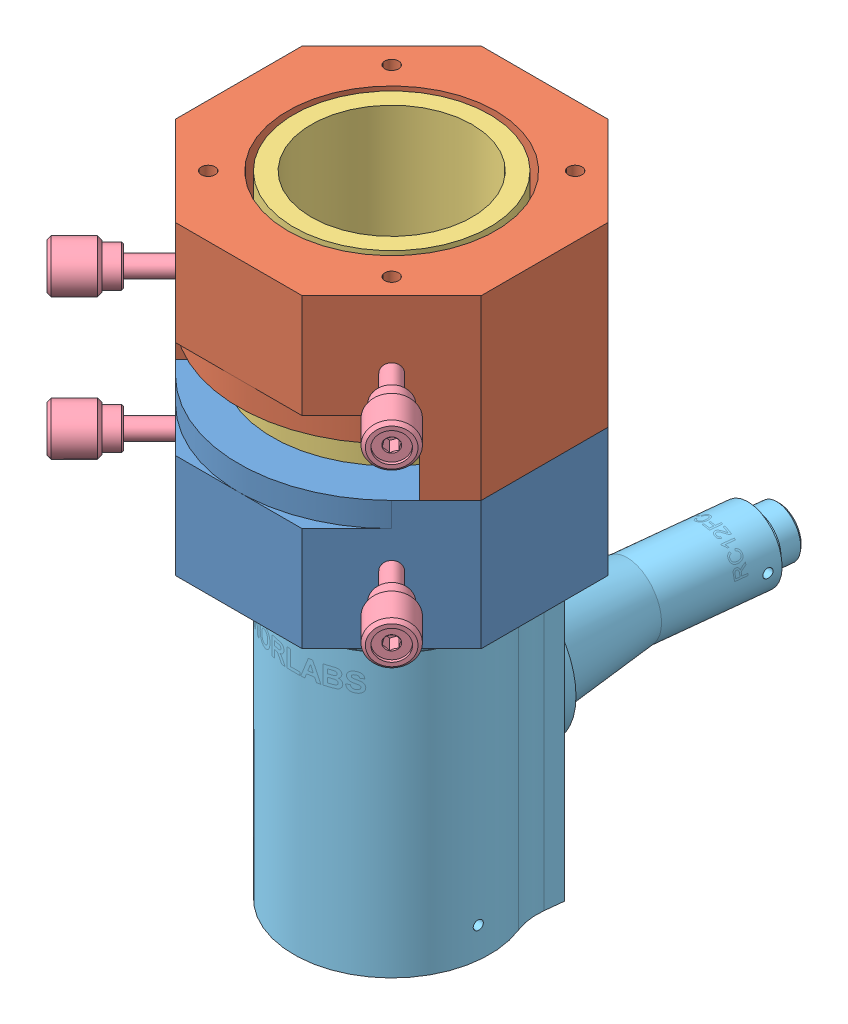
SolidWorks assembly Collimator Allignment Tool, configuration Default. Lengths in mm.
Overall size (62.9 103 91.39).
8 component instances, 5 part files, 15 mates.
Components (placement in the parent):
- CC053-A - Outer Tube Short-1: CC053-A - Outer Tube Short [Default] at (5.4949 13.0758 47.5763) size (50 21 50)
- CC052-A - Outer Tube Long-1: CC052-A - Outer Tube Long [Default] at (5.4949 63.0758 47.5763) x (1 0 0) z (0 0 -1) size (50 29 50)
- CC051-A - Inner Tube-2: CC051-A - Inner Tube [Default] at (5.4949 38.0758 47.5763) x (-0.947211 0 -0.320612) z (0.320612 0 -0.947211) size (39 50 39)
- MAS15-1: MAS15 [Default] at (21.7416 50.6684 64.379) x (-0.146441 -0.97832 0.146441) z (-0.707107 0 -0.707107) size (7.11 7.11 23.88)
- MAS15-2: MAS15 [Default] at (21.7416 22.6684 64.379) x (-0.146441 -0.97832 0.146441) z (-0.707107 0 -0.707107) size (7.11 7.11 23.88)
- MAS15-3: MAS15 [Default] at (-11.8034 50.5446 63.3275) x (-0.558147 0.613957 -0.558147) z (0.707107 0 -0.707107) size (7.11 7.11 23.88)
- MAS15-4: MAS15 [Default] at (-11.8034 27.5446 63.3275) x (-0.558147 0.613957 -0.558147) z (0.707107 0 -0.707107) size (7.11 7.11 23.88)
- RC12FC-P01 - ReflectiveCollimator12mm-1: RC12FC-P01 - ReflectiveCollimator12mm [Default] at (5.4949 -39.9242 47.5763) x (-0.994124 0 -0.10825) z (0 1 0) size (42.2 77.84 57)
Mates (geometry in assembly coordinates):
- Concentric1: concentric: cylinder of CC053-A - Outer Tube Short-1 through (-15.3477 13.0758 56.2096) axis (0 -1 0) radius 1.7; cylinder of CC052-A - Outer Tube Long-1 through (-15.3477 34.0758 56.2096) axis (0 -1 0) radius 1.25
- Concentric2: concentric: cylinder of CC053-A - Outer Tube Short-1 through (26.3374 13.0758 56.2096) axis (0 -1 0) radius 1.7; cylinder of CC052-A - Outer Tube Long-1 through (26.3374 34.0758 56.2096) axis (0 -1 0) radius 1.25
- Coincident5: coincident: plane of CC053-A - Outer Tube Short-1 through (5.4949 34.0758 47.5763) normal (0 1 0); plane of CC052-A - Outer Tube Long-1 through (5.4949 34.0758 47.5763) normal (0 -1 0)
- Concentric4: concentric: cylinder of CC052-A - Outer Tube Long-1 through (5.4949 42.0758 47.5763) axis (0 1 0) radius 17; cylinder of CC051-A - Inner Tube-2 through (5.4949 63.0758 47.5763) axis (0 -1 0) radius 16
- Width5: width: plane of CC052-A - Outer Tube Long-1 through (5.4949 63.0758 47.5763) normal (0 1 0); plane of CC053-A - Outer Tube Short-1 through (5.4949 13.0758 47.5763) normal (0 -1 0); plane of CC051-A - Inner Tube-2 through (5.4949 13.0758 47.5763) normal (0 -1 0); plane of CC051-A - Inner Tube-2 through (5.4949 63.0758 47.5763) normal (0 1 0)
- Concentric6: concentric: cylinder of CC052-A - Outer Tube Long-1 through (23.1725 52.0758 65.254) axis (0.707107 0 0.707107) radius 1.4; cylinder of MAS15-1 through (16.7692 52.0758 58.8506) axis (-0.707107 0 -0.707107) radius 1.5
- Concentric7: concentric: cylinder of CC053-A - Outer Tube Short-1 through (23.1725 24.0758 65.254) axis (0.707107 0 0.707107) radius 1.4; cylinder of MAS15-2 through (16.7692 24.0758 58.8506) axis (-0.707107 0 -0.707107) radius 1.5
- Concentric8: concentric: cylinder of CC052-A - Outer Tube Long-1 through (-12.1828 49.5758 65.254) axis (-0.707107 0 0.707107) radius 1.4; cylinder of MAS15-3 through (-5.7795 49.5758 58.8506) axis (0.707107 0 -0.707107) radius 1.5
- Concentric9: concentric: cylinder of CC053-A - Outer Tube Short-1 through (-12.1828 26.5758 65.254) axis (-0.707107 0 0.707107) radius 1.4; cylinder of MAS15-4 through (-5.7795 26.5758 58.8506) axis (0.707107 0 -0.707107) radius 1.5
- Coincident6: coincident: plane of MAS15-3 through (-19.0992 46.0082 78.657) normal (-0.707107 0 0.707107); plane of MAS15-4 through (-19.0992 23.0082 78.657) normal (-0.707107 0 0.707107)
- Coincident7: coincident: plane of MAS15-1 through (34.1832 57.7607 74.5627) normal (0.707107 0 0.707107); plane of MAS15-2 through (34.1832 29.7607 74.5627) normal (0.707107 0 0.707107)
- Coincident8: coincident: cylinder of CC051-A - Inner Tube-2 through (5.4949 63.0758 47.5763) axis (0 -1 0) radius 16; moEndPointRef_w of MAS15-1
- Coincident9: coincident: cylinder of CC051-A - Inner Tube-2 through (5.4949 63.0758 47.5763) axis (0 -1 0) radius 16; moEndPointRef_w of MAS15-3
- Concentric10: concentric: circle of CC051-A - Inner Tube-2; cylinder of RC12FC-P01 - ReflectiveCollimator12mm-1 through (5.4949 17.0758 47.5763) axis (0 -1 0) radius 13.1445
- Coincident10: coincident: plane of CC051-A - Inner Tube-2 through (5.4949 13.0758 47.5763) normal (0 -1 0); plane of RC12FC-P01 - ReflectiveCollimator12mm-1 through (5.4949 13.0758 47.5763) normal (0 1 0)
